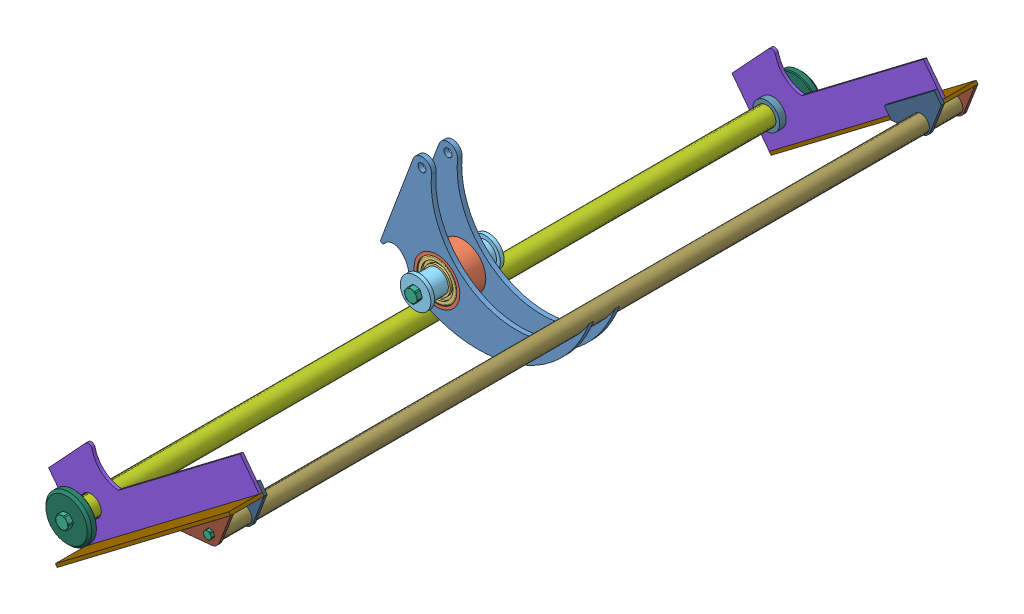
SolidWorks assembly ТП.016.03.00 - Подъем навесного оборудования, configuration 00. Lengths in mm.
Overall size (315.69 301.69 987.2).
34 component instances, 15 part files, 38 mates.
Components (placement in the parent):
- ТП.016.03.01.00 - Рычаг подъема навески-1: ТП.016.03.01.00 - Рычаг подъема навески [00] at (0 0 20) x (0.969039 0.246908 0) z (0 0 1) size (274.94 199.54 40) (flexible)
  - ТП.016.03.01.01 - Зуб подъемника (6мм)-1: ТП.016.03.01.01 - Зуб подъемника (6мм) [--] at origin size (274.94 199.54 6)
  - ТП.016.03.01.02 - Ступица подъема-1: ТП.016.03.01.02 - Ступица подъема [--] at (0 0 -20) x (0.998218 0.059675 0) z (0 0 1) size (60 60 40)
  - ТП.016.03.01.01 - Зуб подъемника (6мм)-2: ТП.016.03.01.01 - Зуб подъемника (6мм) [--] at (0 0 -34) size (274.94 199.54 6)
  - Подшипник ГОСТ 8338-75 -1: Подшипник ГОСТ 8338-75  [Подшипник 205 ГОСТ 8338-75] at (0 0 -7.5) x (0 0 -1) z (0.853055 -0.521822 0) size (15 52 52)
  - Подшипник ГОСТ 8338-75 -2: Подшипник ГОСТ 8338-75  [Подшипник 205 ГОСТ 8338-75] at (0 0 -32.5) x (0 0 -1) z (-0.395474 -0.918477 0) size (15 52 52)
- ТП.016.03.02 - Ось подъема-1: ТП.016.03.02 - Ось подъема [--] x (-0.846104 -0.533017 0) z (0 0 1) size (25 25 86)
- ТП.016.03.03 - Стакан оси подъема-1: ТП.016.03.03 - Стакан оси подъема [--] at (0 0 -20) x (-0.637116 -0.770768 0) z (0 0 -1) size (40 40 28)
- ТП.016.03.03 - Стакан оси подъема-2: ТП.016.03.03 - Стакан оси подъема [--] at (0 0 20) x (0.999679 0.025339 0) z (0 0 1) size (40 40 28)
- Болты с шестигранной головкой кт.В (ГОСТ 7798-70)-1: Болты с шестигранной головкой кт.В (ГОСТ 7798-70) [Болт М10-6gx20(S16) ГОСТ 7798-77] at (0 0 48) x (0 0 -1) z (-0.933904 -0.357524 0) size (26.4 17.6 16)
- Болты с шестигранной головкой кт.В (ГОСТ 7798-70)-2: Болты с шестигранной головкой кт.В (ГОСТ 7798-70) [Болт М10-6gx20(S16) ГОСТ 7798-77] at (0 0 -48) x (0 0 1) z (0.575817 -0.817579 0) size (26.4 17.6 16)
- ТП.016.03.04 - Ось крепления навески-1: ТП.016.03.04 - Ось крепления навески [--] at (-23.515 -52.1776 461.6) size (25 25 943.2)
- ТП.016.03.05.00 - Ложемент-1: ТП.016.03.05.00 - Ложемент [Правый] at (-23.515 -52.1776 449.6) x (0.79654 0.604586 0) z (0 0 1) size (285 120.43 48)
  - ТП.016.03.05.01 - Ложемент бок (4мм)-1: ТП.016.03.05.01 - Ложемент бок (4мм) [--] at origin size (285 93.13 4)
  - ТП.016.03.05.02 - Ложемент низ (4мм)-1: ТП.016.03.05.02 - Ложемент низ (4мм) [--] at (250 -35 -4) size (285 4 44)
  - ТП.016.03.05.03 - Хомут связки (4мм)-1: ТП.016.03.05.03 - Хомут связки (4мм) [--] at (250 -39 -4) size (82.5 38.3 4)
  - ТП.016.03.05.04 - Шайба связки (4мм)-1: ТП.016.03.05.04 - Шайба связки (4мм) [--] at (250 -39 40) size (82.5 23.3 4)
- ТП.016.03.05.00 - Ложемент-2: ТП.016.03.05.00 - Ложемент [Левый] at (-23.515 -52.1776 -445.6) x (0.79654 0.604586 0) z (0 0 1) size (285 120.43 48)
  - ТП.016.03.05.01 - Ложемент бок (4мм)-1: ТП.016.03.05.01 - Ложемент бок (4мм) [--] at origin size (285 93.13 4)
  - ТП.016.03.05.02 - Ложемент низ (4мм)-1: ТП.016.03.05.02 - Ложемент низ (4мм) [--] at (250 -35 -44) size (285 4 44)
  - ТП.016.03.05.03 - Хомут связки (4мм)-1: ТП.016.03.05.03 - Хомут связки (4мм) [--] at (250 -39 4) size (82.5 38.3 4)
  - ТП.016.03.05.04 - Шайба связки (4мм)-1: ТП.016.03.05.04 - Шайба связки (4мм) [--] at (250 -39 -40) size (82.5 23.3 4)
- ТП.016.03.06.00 - Штанга связки-1: ТП.016.03.06.00 - Штанга связки [00] at (-26.1598 98.6116 0) x (0.966166 -0.257922 0) z (0 0 1) size (21.43 21.43 971.2)
  - ТП.016.03.06.01 - Труба связка-1: ТП.016.03.06.01 - Труба связка [--] at (0 0 489.6) size (21.3 21.3 971.2)
  - ТП.016.03.06.02 - Втулка штанги-1: ТП.016.03.06.02 - Втулка штанги [--] at (198.0992 0 485.6) size (18 18 30)
  - ТП.016.03.06.02 - Втулка штанги-2: ТП.016.03.06.02 - Втулка штанги [--] at (216.8746 2.0316 -485.6) x (-0.976855 -0.213903 0) z (0 0 -1) size (18 18 30)
- Болты с шестигранной головкой кт.В (ГОСТ 7798-70)-3: Болты с шестигранной головкой кт.В (ГОСТ 7798-70) [Болт М6-6gx20(S10) ГОСТ 7798-77] at (172.7797 34.4811 489.6) x (0 0 -1) z (0.7882 -0.615419 0) size (24 10.9 10)
- Болты с шестигранной головкой кт.В (ГОСТ 7798-70)-4: Болты с шестигранной головкой кт.В (ГОСТ 7798-70) [Болт М6-6gx20(S10) ГОСТ 7798-77] at (172.7797 34.4811 -489.6) x (0 0 1) z (0.2792 0.960233 0) size (24 10.9 10)
- ТП.016.03.07 - Шайба проставка-1: ТП.016.03.07 - Шайба проставка [--] at (7.7544 4.8068 435) x (0.876683 -0.481068 0) z (0 0 1) size (35 35 8.6)
- ТП.016.03.07 - Шайба проставка-2: ТП.016.03.07 - Шайба проставка [--] at (28.2028 -12.8042 -443.6) x (0.605745 -0.795659 0) z (0 0 1) size (35 35 8.6)
- ТП.016.03.08 - Шайба законцовывающая-1: ТП.016.03.08 - Шайба законцовывающая [--] at (-23.515 -52.1776 471.6) x (0.993979 0.109574 0) z (0 0 1) size (60 60 10)
- ТП.016.03.08 - Шайба законцовывающая-2: ТП.016.03.08 - Шайба законцовывающая [--] at (-23.515 -52.1776 -471.6) x (0.95629 0.292419 0) z (0 0 -1) size (60 60 10)
- Болты с шестигранной головкой кт.В (ГОСТ 7798-70)-5: Болты с шестигранной головкой кт.В (ГОСТ 7798-70) [Болт М10-6gx20(S16) ГОСТ 7798-77] at (-23.515 -52.1776 -481.6) x (0 0 1) z (0.771641 -0.636059 0) size (26.4 17.6 16)
- Болты с шестигранной головкой кт.В (ГОСТ 7798-70)-6: Болты с шестигранной головкой кт.В (ГОСТ 7798-70) [Болт М10-6gx20(S16) ГОСТ 7798-77] at (-23.515 -52.1776 481.6) x (0 0 -1) z (0.165324 -0.986239 0) size (26.4 17.6 16)
Mates (geometry in assembly coordinates):
- Концентричный1: concentric: cylinder of ТП.016.03.01.00 - Рычаг подъема навески-1/Подшипник ГОСТ 8338-75 -1 through (0 0 1012.5) axis (0 0 1) radius 12.5; line of assembly
- Симметричный1: symmetric: plane of ТП.016.03.01.00 - Рычаг подъема навески-1/ТП.016.03.01.01 - Зуб подъемника (6мм)-1 through (53.6344 103.9824 14) normal (0 0 -1); plane of ТП.016.03.01.00 - Рычаг подъема навески-1/ТП.016.03.01.01 - Зуб подъемника (6мм)-2 through (53.6344 103.9824 -14) normal (0 0 1); plane of assembly
- Симметричный2: symmetric: plane of ТП.016.03.02 - Ось подъема-1 through (0 0 43) normal (0 0 1); plane of ТП.016.03.02 - Ось подъема-1 through (0 0 -43) normal (0 0 -1); plane of assembly
- Концентричный2: concentric: cylinder of ТП.016.03.01.00 - Рычаг подъема навески-1/Подшипник ГОСТ 8338-75 -2 through (0 0 987.5) axis (0 0 1) radius 12.5; cylinder of ТП.016.03.02 - Ось подъема-1 through (0 0 0) axis (0 0 1) radius 12.5
- Концентричный3: concentric: cylinder of ТП.016.03.02 - Ось подъема-1 through (0 0 0) axis (0 0 1) radius 12.5; cylinder of ТП.016.03.03 - Стакан оси подъема-1 through (0 0 -1020) axis (0 0 -1) radius 12.5
- Совпадение1: coincident: plane of ТП.016.03.03 - Стакан оси подъема-1 through (-15.4154 12.7423 -43) normal (0 0 1); plane of assembly through (0 0 -43) normal (0 0 -1)
- Совпадение2: coincident: plane of ТП.016.03.03 - Стакан оси подъема-2 through (-0.5068 19.9936 43) normal (0 0 -1); plane of assembly through (0 0 43) normal (0 0 1)
- Концентричный4: concentric: cylinder of ТП.016.03.02 - Ось подъема-1 through (0 0 0) axis (0 0 1) radius 12.5; cylinder of ТП.016.03.03 - Стакан оси подъема-2 through (0 0 1020) axis (0 0 1) radius 15
- Совпадение3: coincident: plane of ТП.016.03.03 - Стакан оси подъема-2 through (-0.133 5.2483 48) normal (0 0 1); plane of Болты с шестигранной головкой кт.В (ГОСТ 7798-70)-1 through (3.1462 -8.2184 48) normal (0 0 -1)
- Концентричный5: concentric: cylinder of ТП.016.03.02 - Ось подъема-1 through (0 0 43) axis (0 0 1) radius 4.25; cylinder of Болты с шестигранной головкой кт.В (ГОСТ 7798-70)-1 through (0 0 1048) axis (0 0 1) radius 5
- Совпадение4: coincident: plane of ТП.016.03.03 - Стакан оси подъема-1 through (-4.0465 3.3449 -48) normal (0 0 -1); plane of Болты с шестигранной головкой кт.В (ГОСТ 7798-70)-2 through (-7.1947 -5.0672 -48) normal (0 0 1)
- Концентричный6: concentric: cylinder of ТП.016.03.02 - Ось подъема-1 through (0 0 -43) axis (0 0 -1) radius 4.25; cylinder of Болты с шестигранной головкой кт.В (ГОСТ 7798-70)-2 through (0 0 -1048) axis (0 0 -1) radius 5
- Концентричный7: concentric: cylinder of ТП.016.03.04 - Ось крепления навески-1 through (-23.515 -52.1776 -35.3553) axis (0 0 1) radius 12.5; circle of assembly
- Симметричный3: symmetric: plane of ТП.016.03.04 - Ось крепления навески-1 through (-23.515 -52.1776 -471.6) normal (0 0 -1); plane of ТП.016.03.04 - Ось крепления навески-1 through (-23.515 -52.1776 471.6) normal (0 0 1); plane of assembly
- Концентричный8: concentric: cylinder of ТП.016.03.04 - Ось крепления навески-1 through (-23.515 -52.1776 -35.3553) axis (0 0 1) radius 12.5; cylinder of ТП.016.03.05.00 - Ложемент-1/ТП.016.03.05.01 - Ложемент бок (4мм)-1 through (-23.515 -52.1776 445.6) axis (0 0 1) radius 13.5
- Концентричный9: concentric: cylinder of ТП.016.03.04 - Ось крепления навески-1 through (-23.515 -52.1776 -35.3553) axis (0 0 1) radius 12.5; cylinder of ТП.016.03.05.00 - Ложемент-2/ТП.016.03.05.01 - Ложемент бок (4мм)-1 through (-23.515 -52.1776 -449.6) axis (0 0 1) radius 13.5
- Концентричный10: concentric: cylinder of ТП.016.03.05.00 - Ложемент-1/ТП.016.03.05.03 - Хомут связки (4мм)-1 through (172.7797 34.4811 441.6) axis (0 0 1) radius 10.65; cylinder of ТП.016.03.06.00 - Штанга связки-1/ТП.016.03.06.01 - Труба связка-1 through (172.7797 34.4811 -30.1227) axis (0 0 1) radius 10.65
- Совпадение9: coincident: plane of ТП.016.03.05.00 - Ложемент-1/ТП.016.03.05.04 - Шайба связки (4мм)-1 through (172.7797 34.4811 485.6) normal (0 0 -1); plane of ТП.016.03.06.00 - Штанга связки-1/ТП.016.03.06.01 - Труба связка-1 through (172.7797 34.4811 485.6) normal (0 0 1)
- Концентричный11: concentric: cylinder of ТП.016.03.05.00 - Ложемент-2/ТП.016.03.05.03 - Хомут связки (4мм)-1 through (172.7797 34.4811 -445.6) axis (0 0 1) radius 10.65; cylinder of ТП.016.03.06.00 - Штанга связки-1/ТП.016.03.06.01 - Труба связка-1 through (172.7797 34.4811 -30.1227) axis (0 0 1) radius 10.65
- Касательность1: tangent: cylinder of ТП.016.03.01.00 - Рычаг подъема навески-1/ТП.016.03.01.01 - Зуб подъемника (6мм)-1 through (103.5561 107.2717 14) axis (0 0 1) radius 111.1009; cylinder of ТП.016.03.06.00 - Штанга связки-1/ТП.016.03.06.01 - Труба связка-1 through (172.7797 34.4811 -30.1227) axis (0 0 1) radius 10.65
- Совпадение10: coincident: plane of ТП.016.03.05.00 - Ложемент-1/ТП.016.03.05.04 - Шайба связки (4мм)-1 through (172.7797 34.4811 489.6) normal (0 0 1); plane of Болты с шестигранной головкой кт.В (ГОСТ 7798-70)-3 through (176.1337 38.7768 489.6) normal (0 0 -1)
- Концентричный12: concentric: cylinder of ТП.016.03.06.00 - Штанга связки-1/ТП.016.03.06.02 - Втулка штанги-1 through (172.7797 34.4811 485.6) axis (0 0 1) radius 2.5; cylinder of Болты с шестигранной головкой кт.В (ГОСТ 7798-70)-3 through (172.7797 34.4811 1489.6) axis (0 0 1) radius 3
- Концентричный13: concentric: cylinder of ТП.016.03.06.00 - Штанга связки-1/ТП.016.03.06.02 - Втулка штанги-2 through (172.7797 34.4811 -485.6) axis (0 0 -1) radius 2.5; cylinder of Болты с шестигранной головкой кт.В (ГОСТ 7798-70)-4 through (172.7797 34.4811 -1489.6) axis (0 0 -1) radius 3
- Совпадение11: coincident: plane of ТП.016.03.05.00 - Ложемент-2/ТП.016.03.05.04 - Шайба связки (4мм)-1 through (172.7797 34.4811 -489.6) normal (0 0 -1); plane of Болты с шестигранной головкой кт.В (ГОСТ 7798-70)-4 through (178.0129 32.9594 -489.6) normal (0 0 1)
- Концентричный14: concentric: cylinder of ТП.016.03.04 - Ось крепления навески-1 through (-23.515 -52.1776 -35.3553) axis (0 0 1) radius 12.5; cylinder of ТП.016.03.07 - Шайба проставка-1 through (-23.515 -52.1776 495.0975) axis (0 0 -1) radius 12.5
- Расстояние1: distance = 28 mm: plane of ТП.016.03.04 - Ось крепления навески-1 through (-23.515 -52.1776 471.6) normal (0 0 1); plane of ТП.016.03.07 - Шайба проставка-1 through (49.2422 -92.6444 443.6) normal (0 0 1)
- Расстояние2: distance = 2 mm: plane of ТП.016.03.05.00 - Ложемент-1/ТП.016.03.05.01 - Ложемент бок (4мм)-1 through (15.1916 21.5311 445.6) normal (0 0 -1); plane of ТП.016.03.07 - Шайба проставка-1 through (49.2422 -92.6444 443.6) normal (0 0 1)
- Концентричный15: concentric: cylinder of ТП.016.03.04 - Ось крепления навески-1 through (-23.515 -52.1776 -35.3553) axis (0 0 1) radius 12.5; cylinder of ТП.016.03.07 - Шайба проставка-2 through (-23.515 -52.1776 -383.5025) axis (0 0 -1) radius 12.5
- Расстояние3: distance = 28 mm: plane of ТП.016.03.07 - Шайба проставка-2 through (-23.515 -52.1776 -443.6) normal (0 0 -1); plane of ТП.016.03.04 - Ось крепления навески-1 through (-23.515 -52.1776 -471.6) normal (0 0 -1)
- Расстояние4: distance = 2 mm: plane of ТП.016.03.05.00 - Ложемент-2/ТП.016.03.05.01 - Ложемент бок (4мм)-1 through (15.1916 21.5311 -445.6) normal (0 0 1); plane of ТП.016.03.07 - Шайба проставка-2 through (-23.515 -52.1776 -443.6) normal (0 0 -1)
- Совпадение12: coincident: plane of ТП.016.03.04 - Ось крепления навески-1 through (-23.515 -52.1776 471.6) normal (0 0 1); plane of ТП.016.03.08 - Шайба законцовывающая-1 through (-23.515 -52.1776 471.6) normal (0 0 -1)
- Концентричный16: concentric: cylinder of ТП.016.03.04 - Ось крепления навески-1 through (-23.515 -52.1776 471.6) axis (0 0 1) radius 4.25; cylinder of ТП.016.03.08 - Шайба законцовывающая-1 through (-23.515 -52.1776 481.6) axis (0 0 -1) radius 5.25
- Совпадение13: coincident: plane of ТП.016.03.04 - Ось крепления навески-1 through (-23.515 -52.1776 -471.6) normal (0 0 -1); plane of ТП.016.03.08 - Шайба законцовывающая-2 through (-23.515 -52.1776 -471.6) normal (0 0 1)
- Концентричный17: concentric: cylinder of ТП.016.03.04 - Ось крепления навески-1 through (-23.515 -52.1776 -471.6) axis (0 0 -1) radius 4.25; cylinder of ТП.016.03.08 - Шайба законцовывающая-2 through (-23.515 -52.1776 -481.6) axis (0 0 1) radius 5.25
- Совпадение14: coincident: plane of ТП.016.03.08 - Шайба законцовывающая-2 through (-23.515 -52.1776 -481.6) normal (0 0 -1); plane of Болты с шестигранной головкой кт.В (ГОСТ 7798-70)-5 through (-29.1123 -58.9681 -481.6) normal (0 0 1)
- Концентричный18: concentric: cylinder of ТП.016.03.08 - Шайба законцовывающая-2 through (-23.515 -52.1776 -481.6) axis (0 0 1) radius 5.25; cylinder of Болты с шестигранной головкой кт.В (ГОСТ 7798-70)-5 through (-23.515 -52.1776 -1481.6) axis (0 0 -1) radius 5
- Совпадение15: coincident: plane of ТП.016.03.08 - Шайба законцовывающая-1 through (-23.515 -52.1776 481.6) normal (0 0 1); plane of Болты с шестигранной головкой кт.В (ГОСТ 7798-70)-6 through (-14.8361 -50.7228 481.6) normal (0 0 -1)
- Концентричный19: concentric: cylinder of ТП.016.03.08 - Шайба законцовывающая-1 through (-23.515 -52.1776 481.6) axis (0 0 -1) radius 5.25; cylinder of Болты с шестигранной головкой кт.В (ГОСТ 7798-70)-6 through (-23.515 -52.1776 1481.6) axis (0 0 1) radius 5
